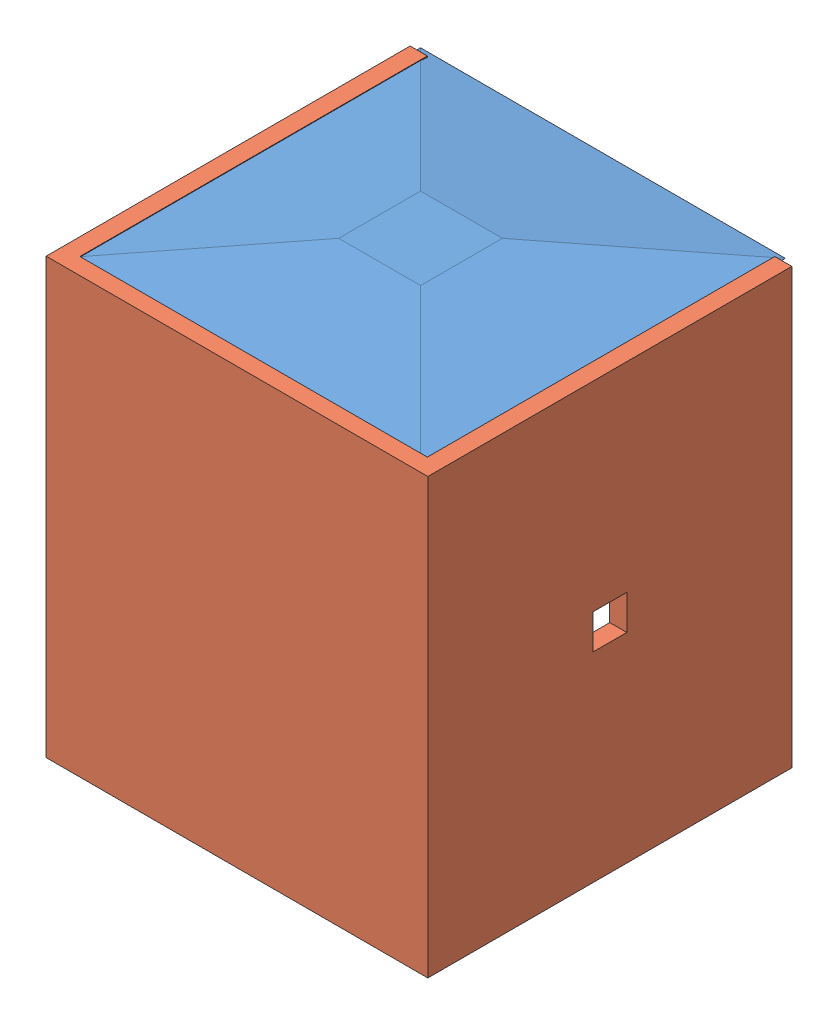
SolidWorks assembly canasta_cuadrada, configuration Predeterminado. Lengths in mm.
Overall size (55.8 65.73 54.07).
3 component instances, 2 part files, 0 mates.
Components (placement in the parent):
- base_canasta2-1: base_canasta2 [Predeterminado] at (13.4907 -5.1974 50.695) size (53.34 2.54 53.34)
- pared_cansta2-1: pared_cansta2 [Predeterminado] at (27.215 -5.2833 27.493) size (55.8 63.5 53.22)
- base_canasta2-2: base_canasta2 [Predeterminado] at (13.2939 57.9067 50.673) size (53.34 2.54 53.34)
